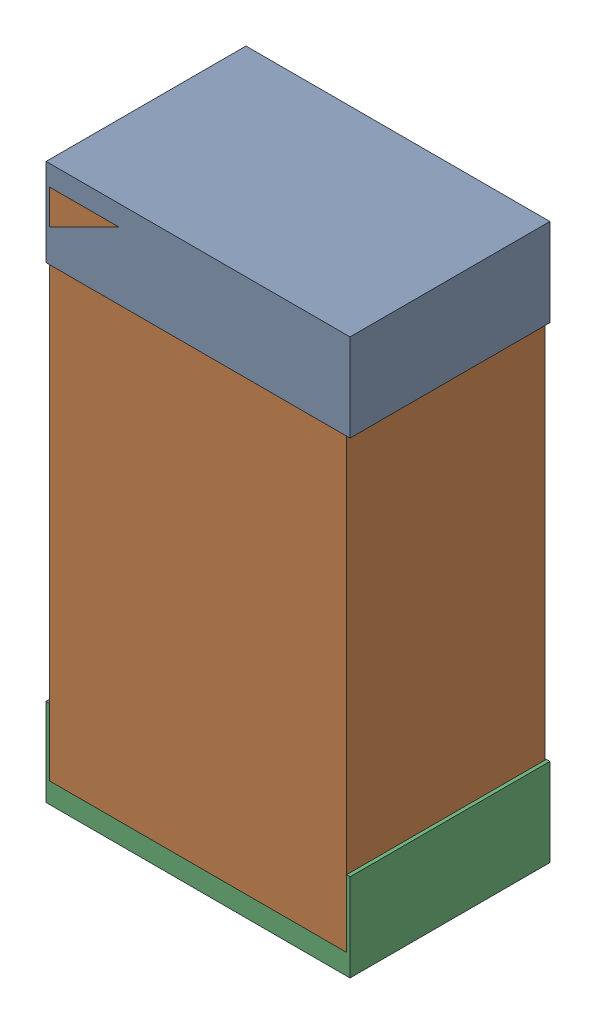
SolidWorks assembly R24Kanaloa_v2.0.0_Motor, configuration Default. Lengths in mm.
Overall size (1.3 2.38 0.85).
6 component instances, 2 part files, 0 mates.
Components (placement in the parent):
- 330415056-1: 330415056 [Default] at (38.354 99.806 -1.9574) size (1.3 0.38 0.85)
  - Extruded_2-1: Extruded_2 [Default] at origin size (1.3 0.38 0.85)
- 334787376-1: 334787376 [Default] at (38.354 98.806 -1.9524) size (1.27 2.2 0.85)
  - Extruded_16-1: Extruded_16 [Default] at origin size (1.27 2.2 0.85)
- 330415056-2: 330415056 [Default] at (38.354 97.806 -1.9574) size (1.3 0.38 0.85)
  - Extruded_2-1: Extruded_2 [Default] at origin size (1.3 0.38 0.85)
